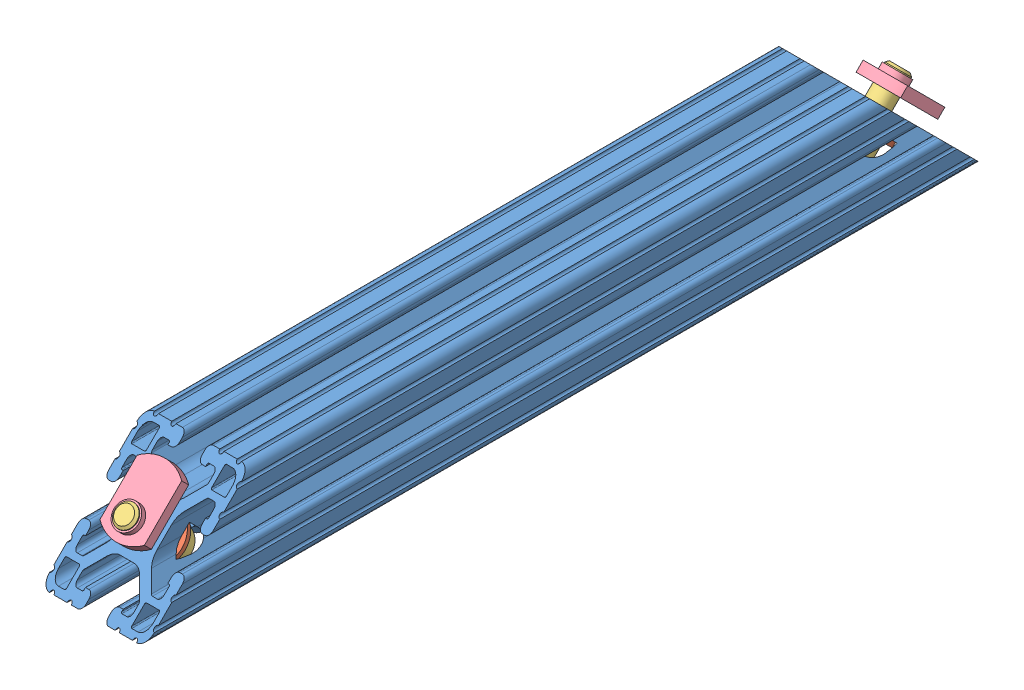
SolidWorks assembly 8020-2561-$PARTNUMBER, configuration Default. Lengths in mm.
Overall size (38.1 42.71 306.17).
9 component instances, 4 part files, 4 mates.
Components (placement in the parent):
- 8020-2561-$PARTNUMBER_2561-1: 8020-2561-$PARTNUMBER_2561 [Default] at (-69.3661 13.3247 180.1496) size (38.1 38.69 304.8)
- 8020-2561-$PARTNUMBER_15sHW-1: 8020-2561-$PARTNUMBER_15sHW [Default] at (-67.9544 4.9378 155.4914) x (1 0 0) z (0 0.707107 -0.707107) size (17.58 26.99 26.64)
  - 8020-2561-$PARTNUMBER_3260-1: 8020-2561-$PARTNUMBER_3260 [Default] at (-1.4117 -2.7079 1.9649) size (17.58 1.68 17.58)
  - 8020-2561-$PARTNUMBER_3112-1: 8020-2561-$PARTNUMBER_3112 [3112] at (-1.4117 6.0678 1.9649) x (0 -1 0) z (0 0 1) size (26.99 11.91 11.91)
  - 8020-2561-$PARTNUMBER_3278-1: 8020-2561-$PARTNUMBER_3278 [Default] at (-1.4117 -15.8905 7.3243) x (0 0 1) z (0 -1 0) size (24.99 16.21 5.64)
- 8020-2561-$PARTNUMBER_15sHW-2: 8020-2561-$PARTNUMBER_15sHW [Default] at (-67.9544 7.7165 -97.2134) x (1 0 0) z (0 -0.707107 -0.707107) size (17.58 26.99 26.64)
  - 8020-2561-$PARTNUMBER_3260-1: 8020-2561-$PARTNUMBER_3260 [Default] at (-1.4117 -2.7079 1.9649) size (17.58 1.68 17.58)
  - 8020-2561-$PARTNUMBER_3112-1: 8020-2561-$PARTNUMBER_3112 [3112] at (-1.4117 6.0678 1.9649) x (0 -1 0) z (0 0 1) size (26.99 11.91 11.91)
  - 8020-2561-$PARTNUMBER_3278-1: 8020-2561-$PARTNUMBER_3278 [Default] at (-1.4117 -15.8905 7.3243) x (0 0 1) z (0 -1 0) size (24.99 16.21 5.64)
Mates (geometry in assembly coordinates):
- Concentric11: concentric anti-aligned: cylinder of 8020-2561-$PARTNUMBER_2561-1 through (-69.3661 20.6885 168.4635) axis (0 -0.707107 -0.707107) radius 4.1656; cylinder of 8020-2561-$PARTNUMBER_15sHW-1/8020-2561-$PARTNUMBER_3260-1 through (-69.3661 7.6492 155.4241) axis (0 0.707107 0.707107) radius 4.4323
- Coincident11: coincident anti-aligned: plane of 8020-2561-$PARTNUMBER_2561-1 through (-69.3661 8.8346 156.6095) normal (0 -0.707107 -0.707107); plane of 8020-2561-$PARTNUMBER_15sHW-1/8020-2561-$PARTNUMBER_3260-1 through (-69.3661 8.8346 156.6095) normal (0 0.707107 0.707107)
- Concentric21: concentric anti-aligned: cylinder of 8020-2561-$PARTNUMBER_2561-1 through (-69.3661 20.6885 -112.9642) axis (0 -0.707107 0.707107) radius 4.1656; cylinder of 8020-2561-$PARTNUMBER_15sHW-2/8020-2561-$PARTNUMBER_3260-1 through (-69.3661 7.6492 -99.9248) axis (0 0.707107 -0.707107) radius 4.4323
- Coincident21: coincident anti-aligned: plane of 8020-2561-$PARTNUMBER_2561-1 through (-69.3661 8.8346 -101.1102) normal (0 -0.707107 0.707107); plane of 8020-2561-$PARTNUMBER_15sHW-2/8020-2561-$PARTNUMBER_3260-1 through (-69.3661 8.8346 -101.1102) normal (0 0.707107 -0.707107)
